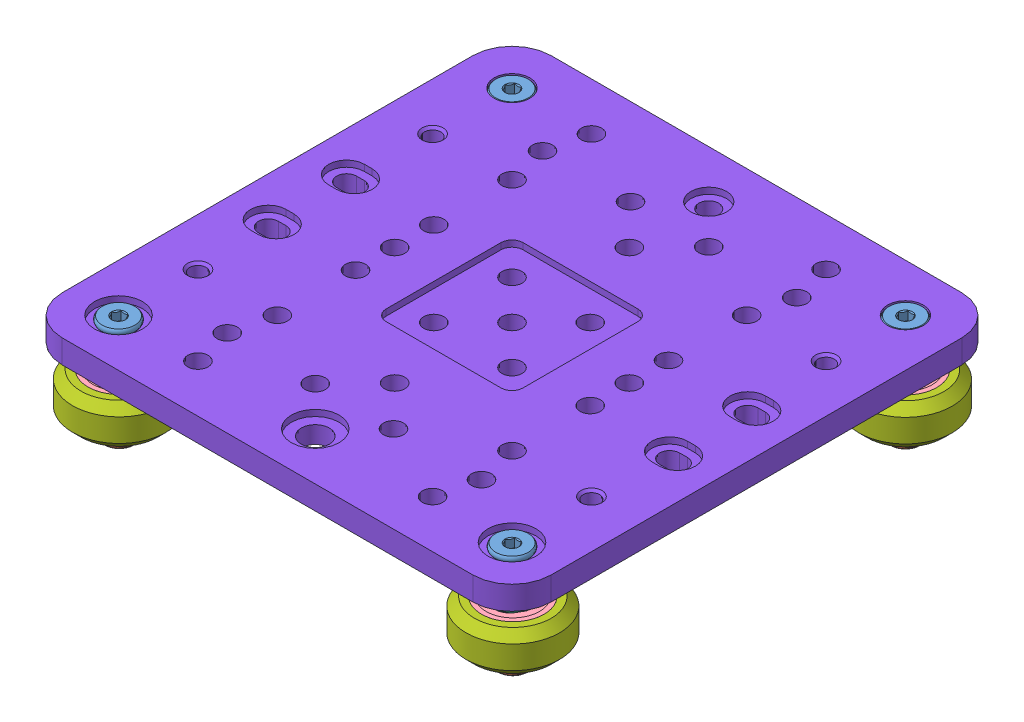
SolidWorks assembly XLarge C-Beam Gantry Kit, configuration Predeterminado. Lengths in mm.
Overall size (125 27.2 125).
30 component instances, 8 part files, 0 mates.
Components (placement in the parent):
- XLarge C-Beam Gantry Kit.step-1: XLarge C-Beam Gantry Kit.step [Predeterminado] at origin size (125 27.2 125)
  - Low Profile Screw M5 v1.step-1: Low Profile Screw M5 v1.step [Predeterminado] at (50.3 -18.5598 -47.3741) x (0 -1 0) z (0 0 -1) size (27 9 9)
  - Nylon Insert Lock Nut M5.step-1: Nylon Insert Lock Nut M5.step [Predeterminado] at (50.3 -19.1598 -47.3741) x (1 0 0) z (0 0 -1) size (8 5 9.24)
  - Aluminum Spacer 6mm.step-1: Aluminum Spacer 6mm.step [Predeterminado] at (50.3 -2.9598 -47.3741) x (1 0 0) z (0 -1 0) size (10 10 6)
  - Ball Bearing 5 x 16 x 5.step-1: Ball Bearing 5 x 16 x 5.step [Predeterminado] at (50.3 -11.4598 -47.3741) x (0 -1 0) z (0 0 -1) size (5 16 16)
  - Precision Shim 8 x 5 x 1.step-1: Precision Shim 8 x 5 x 1.step [Predeterminado] at (50.3 -13.5598 -47.3741) x (1 0 0) z (0 0 -1) size (8 1 8)
  - Ball Bearing 5 x 16 x 5.step-2: Ball Bearing 5 x 16 x 5.step [Predeterminado] at (50.3 -16.6598 -47.3741) x (0 -1 0) z (0 0 -1) size (5 16 16)
  - Low Profile Screw M5 v1.step-2: Low Profile Screw M5 v1.step [Predeterminado] at (-50.3 -18.5598 53.2259) x (0 -1 0) z (0 0 -1) size (27 9 9)
  - Nylon Insert Lock Nut M5.step-2: Nylon Insert Lock Nut M5.step [Predeterminado] at (-50.3 -19.1598 53.0159) x (-1 0 0) z (0 0 1) size (8 5 9.24)
  - Ball Bearing 5 x 16 x 5.step-3: Ball Bearing 5 x 16 x 5.step [Predeterminado] at (-50.3 -11.4598 53.0159) x (0 -1 0) z (0 0 1) size (5 16 16)
  - Precision Shim 8 x 5 x 1.step-2: Precision Shim 8 x 5 x 1.step [Predeterminado] at (-50.3 -13.5598 53.0159) x (-1 0 0) z (0 0 1) size (8 1 8)
  - Ball Bearing 5 x 16 x 5.step-4: Ball Bearing 5 x 16 x 5.step [Predeterminado] at (-50.3 -16.6598 53.0159) x (0 -1 0) z (0 0 1) size (5 16 16)
  - Eccentric Spacer 6mm v1.step-1: Eccentric Spacer 6mm v1.step [Predeterminado] at (-50.3 -2.9598 53.2259) x (-1 0 0) z (0 0 1) size (11.55 8.5 10)
  - Xtreme Solid V Wheel.step-1: Xtreme Solid V Wheel.step [Predeterminado] at (50.3 -14.0598 -47.3741) x (0 -1 0) z (0 0 1) size (10.2 23.9 23.9)
  - Xtreme Solid V Wheel.step-2: Xtreme Solid V Wheel.step [Predeterminado] at (-50.3 -14.0598 53.0159) x (0 -1 0) z (0 0 1) size (10.2 23.9 23.9)
  - C-Beam Gantry Plate XLarge.step-1: C-Beam Gantry Plate XLarge.step [Predeterminado] at (0 -2.9598 2.9259) x (1 0 0) z (0 1 0) size (125 125 6)
  - Eccentric Spacer 6mm v1.step-2: Eccentric Spacer 6mm v1.step [Predeterminado] at (50.3 -2.9598 53.2259) x (-1 0 0) z (0 0 1) size (11.55 8.5 10)
  - Xtreme Solid V Wheel.step-3: Xtreme Solid V Wheel.step [Predeterminado] at (50.3 -14.0598 53.0159) x (0 -1 0) z (0 0 1) size (10.2 23.9 23.9)
  - Nylon Insert Lock Nut M5.step-3: Nylon Insert Lock Nut M5.step [Predeterminado] at (50.3 -19.1598 53.0159) x (-1 0 0) z (0 0 1) size (8 5 9.24)
  - Low Profile Screw M5 v1.step-3: Low Profile Screw M5 v1.step [Predeterminado] at (50.3 -18.5598 53.2259) x (0 -1 0) z (0 0 -1) size (27 9 9)
  - Ball Bearing 5 x 16 x 5.step-5: Ball Bearing 5 x 16 x 5.step [Predeterminado] at (50.3 -11.4598 53.0159) x (0 -1 0) z (0 0 1) size (5 16 16)
  - Precision Shim 8 x 5 x 1.step-3: Precision Shim 8 x 5 x 1.step [Predeterminado] at (50.3 -13.5598 53.0159) x (-1 0 0) z (0 0 1) size (8 1 8)
  - Ball Bearing 5 x 16 x 5.step-6: Ball Bearing 5 x 16 x 5.step [Predeterminado] at (50.3 -16.6598 53.0159) x (0 -1 0) z (0 0 1) size (5 16 16)
  - Nylon Insert Lock Nut M5.step-4: Nylon Insert Lock Nut M5.step [Predeterminado] at (-50.3 -19.1598 -47.3741) x (1 0 0) z (0 0 -1) size (8 5 9.24)
  - Aluminum Spacer 6mm.step-2: Aluminum Spacer 6mm.step [Predeterminado] at (-50.3 -2.9598 -47.3741) x (1 0 0) z (0 -1 0) size (10 10 6)
  - Ball Bearing 5 x 16 x 5.step-7: Ball Bearing 5 x 16 x 5.step [Predeterminado] at (-50.3 -11.4598 -47.3741) x (0 -1 0) z (0 0 -1) size (5 16 16)
  - Low Profile Screw M5 v1.step-4: Low Profile Screw M5 v1.step [Predeterminado] at (-50.3 -18.5598 -47.3741) x (0 -1 0) z (0 0 -1) size (27 9 9)
  - Precision Shim 8 x 5 x 1.step-4: Precision Shim 8 x 5 x 1.step [Predeterminado] at (-50.3 -13.5598 -47.3741) x (1 0 0) z (0 0 -1) size (8 1 8)
  - Ball Bearing 5 x 16 x 5.step-8: Ball Bearing 5 x 16 x 5.step [Predeterminado] at (-50.3 -16.6598 -47.3741) x (0 -1 0) z (0 0 -1) size (5 16 16)
  - Xtreme Solid V Wheel.step-4: Xtreme Solid V Wheel.step [Predeterminado] at (-50.3 -14.0598 -47.3741) x (0 -1 0) z (0 0 1) size (10.2 23.9 23.9)
